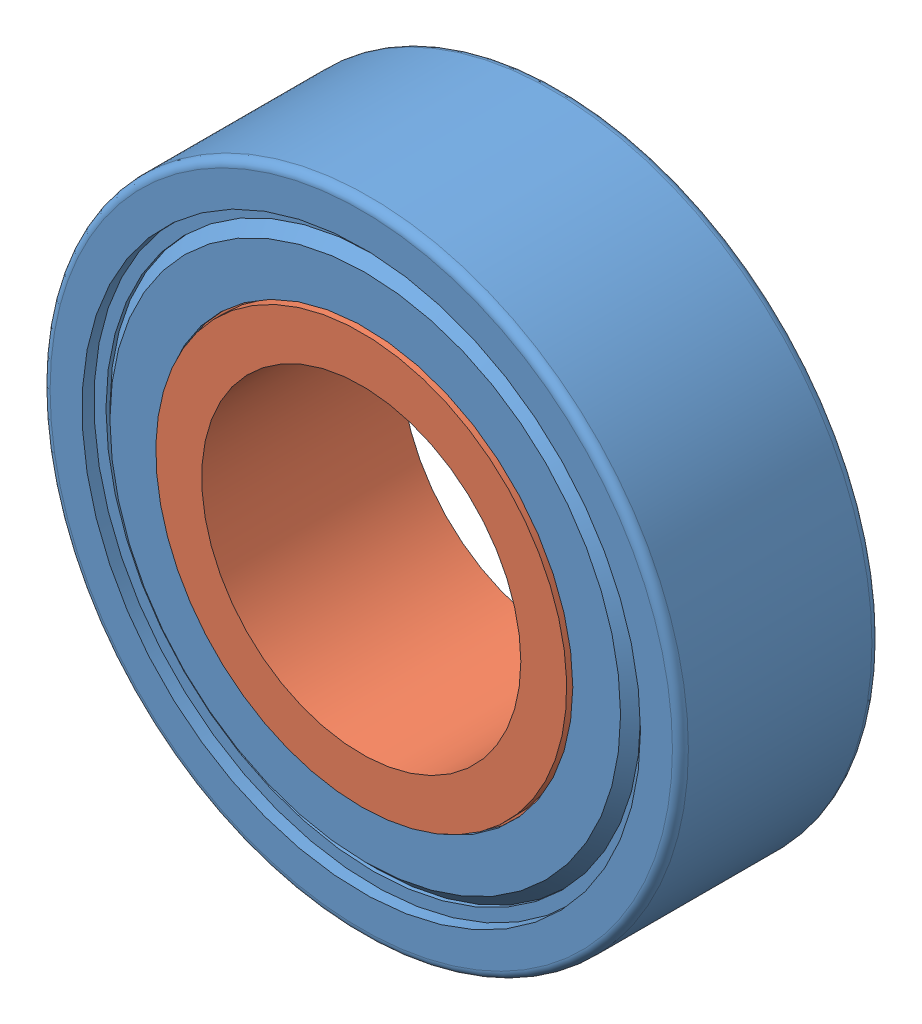
SolidWorks assembly 688ZZ Bearing Assembly, configuration Default. Lengths in mm.
Overall size (16 16 5).
13 component instances, 4 part files, 5 mates.
Components (placement in the parent):
- Outer Ring-1: Outer Ring [Default] at origin size (16 16 5)
- Inner Ring-1: Inner Ring [Default] x (-0.241565 -0.970385 0) z (0 0 1) size (10.6 10.6 5)
- Cage-1: Cage [Default] x (0.535517 0.844524 0) z (0 0 1) size (13.01 13.06 2.21)
- 2mm Ball Bearing-1: 2mm Ball Bearing [Default] at (-5.0671 3.2131 0) x (0.050652 0.835774 0.546732) z (0.977207 -0.154478 0.145614) size (2 2 2)
- 2mm Ball Bearing-2: 2mm Ball Bearing [Default] at (-5.988 -0.3789 0) x (-0.450278 0.705928 0.546732) z (0.881377 0.449412 0.145614) size (2 2 2)
- 2mm Ball Bearing-3: 2mm Ball Bearing [Default] at (-4.6217 -3.8262 0) x (-0.779216 0.306441 0.546732) z (0.448891 0.881642 0.145614) size (2 2 2)
- 2mm Ball Bearing-4: 2mm Ball Bearing [Default] at (-1.49 -5.812 0) x (-0.810521 -0.210096 0.546732) z (-0.155056 0.977115 0.145614) size (2 2 2)
- 2mm Ball Bearing-5: 2mm Ball Bearing [Default] at (2.2108 -5.5778 0) x (-0.532234 -0.646383 0.546732) z (-0.699777 0.699363 0.145614) size (2 2 2)
- 2mm Ball Bearing-6: 2mm Ball Bearing [Default] at (5.0671 -3.2131 0) x (-0.050652 -0.835774 0.546732) z (-0.977207 0.154478 0.145614) size (2 2 2)
- 2mm Ball Bearing-7: 2mm Ball Bearing [Default] at (5.988 0.3789 0) x (0.450278 -0.705928 0.546732) z (-0.881377 -0.449412 0.145614) size (2 2 2)
- 2mm Ball Bearing-8: 2mm Ball Bearing [Default] at (4.6217 3.8262 0) x (0.779216 -0.306441 0.546732) z (-0.448891 -0.881642 0.145614) size (2 2 2)
- 2mm Ball Bearing-9: 2mm Ball Bearing [Default] at (1.49 5.812 0) x (0.810521 0.210096 0.546732) z (0.155056 -0.977115 0.145614) size (2 2 2)
- 2mm Ball Bearing-10: 2mm Ball Bearing [Default] at (-2.2108 5.5778 0) x (0.532234 0.646383 0.546732) z (0.699777 -0.699363 0.145614) size (2 2 2)
Mates (geometry in assembly coordinates):
- Concentric1: concentric aligned: cylinder of Outer Ring-1 through (0 0 6.7554) axis (0 0 1) radius 6.7; circle of Cage-1
- Tangent13: tangent anti-aligned: torus of Outer Ring-1; sphere of 2mm Ball Bearing-1
- Concentric2: concentric: sphere of assembly; point of Cage-1; sphere of 2mm Ball Bearing-1
- Tangent14: tangent anti-aligned: torus of Inner Ring-1; sphere of 2mm Ball Bearing-1
- Concentric3: concentric aligned: cylinder of Outer Ring-1 through (0 0 6.7554) axis (0 0 1) radius 5.2029; cylinder of Inner Ring-1 through (0 0 6.7554) axis (0 0 1) radius 5.3
